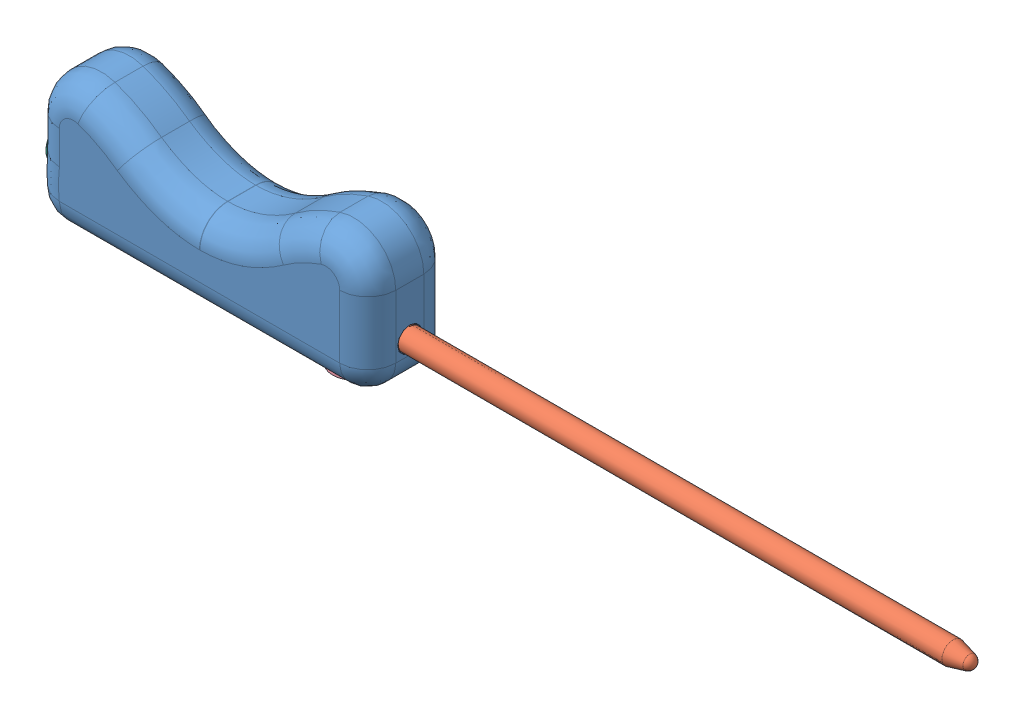
SolidWorks assembly Assem2, configuration Default. Lengths in mm.
Overall size (413.55 64.07 39.53).
7 component instances, 6 part files, 6 mates.
Components (placement in the parent):
- Handle 1 Senior Design-1: Handle 1 Senior Design [Default] at origin size (152.42 60.32 39.53)
- Sheath 1 Senior Design-1: Sheath 1 Senior Design [Default] at (408.4294 -19.05 19.05) x (0 -0.997803 -0.066246) z (0 -0.066246 0.997803) size (10.83 273.41 11.68)
- button 1-1: button 1 [Default] at (101.6 -40.9897 19.05) x (0.979591 0 0.201) z (0 1 0) size (12.7 12.7 8.89)
- button 2-2: button 2 [Default] at (127 -41.2403 19.05) x (0.861828 0 0.5072) z (0 1 0) size (19.05 19.05 8.89)
- LED-1: LED [Default] at (19.05 -31.8525 25.4) x (0.991437 0 -0.130583) z (0 -1 0) size (6.1 6.1 10)
- LED-2: LED [Default] at (19.05 -31.6962 12.7) x (0.985886 0 -0.167416) z (0 -1 0) size (6.1 6.1 10)
- speaker-1: speaker [Default] at (6.9212 -19.05 19.05) x (0 -0.093177 0.99565) z (-1 0 0) size (19.54 19.57 12.05)
Mates (geometry in assembly coordinates):
- Concentric1: concentric anti-aligned: cylinder of Handle 1 Senior Design-1 through (146.05 -19.05 19.05) axis (1 0 0) radius 5.5; circle of Sheath 1 Senior Design-1
- Concentric2: concentric anti-aligned: cylinder of Handle 1 Senior Design-1 through (101.6 -31.75 19.05) axis (0 -1 0) radius 6.35; circle of button 1-1
- Concentric3: concentric anti-aligned: circle of Handle 1 Senior Design-1; circle of button 2-2
- Concentric5: concentric anti-aligned: cylinder of Handle 1 Senior Design-1 through (19.05 -31.75 25.4) axis (0 -1 0) radius 3; circle of LED-1
- Concentric6: concentric anti-aligned: cylinder of Handle 1 Senior Design-1 through (19.05 -31.75 12.7) axis (0 -1 0) radius 3; circle of LED-2
- Concentric9: concentric anti-aligned: cylinder of Handle 1 Senior Design-1 through (6.35 -19.05 19.05) axis (-1 0 0) radius 9.525; cylinder of speaker-1 through (-5.0788 -19.05 19.05) axis (1 0 0) radius 9.525
